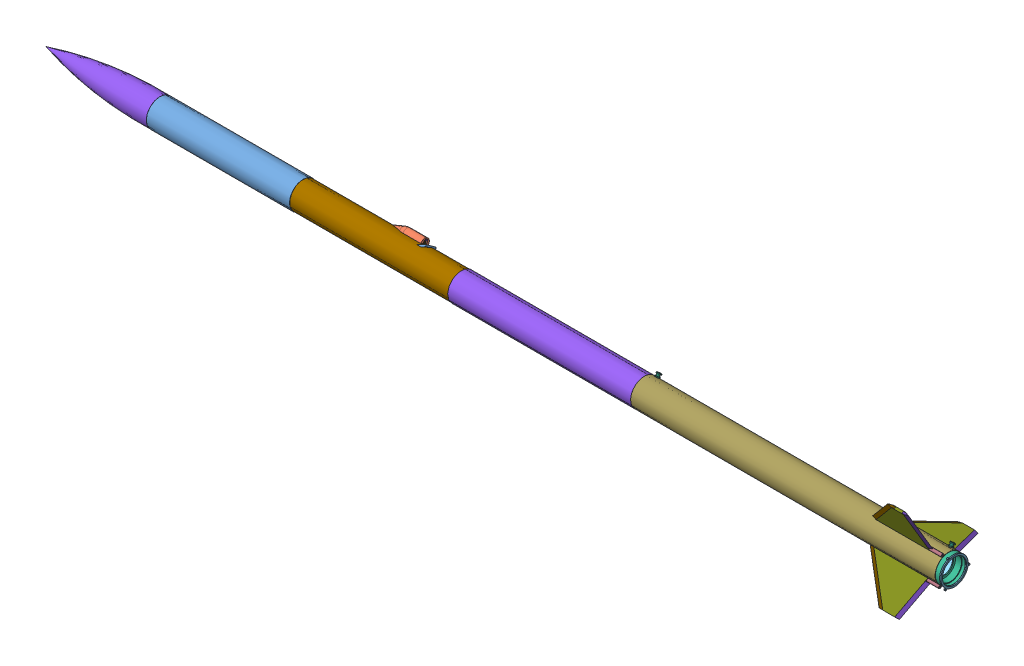
SolidWorks assembly Mudd II, configuration Default. Lengths in mm.
Overall size (1923.22 249.85 252.65).
58 component instances, 43 part files, 15 mates.
Components (placement in the parent):
- Drogue Parachute Assembly-1: Drogue Parachute Assembly [Default] at (16.0079 52.1439 -43.8729) size (341.12 76.5 76.5)
  - Drogue Tube-1: Drogue Tube [Default] at (-135.6643 44.9583 41.0442) size (303.02 58.17 58.17)
  - Drogue Coupler Tube-1: Drogue Coupler Tube [Default] at (205.4577 44.9583 41.0442) x (0 -0.693072 0.720868) z (-1 0 0) size (54.1 54.1 88.9)
  - Drogue Bulk Head (without aluminum)-1: Drogue Bulk Head (without aluminum) [Default] at (194.0277 44.9583 41.0442) x (0 0.776678 -0.629898) z (-1 0 0) size (51.82 50.33 3.81)
  - Drouge Bulk Head (with aluminum)-1: Drouge Bulk Head (with aluminum) [Default] at (194.0277 44.9583 41.0442) x (0 0.776678 -0.629898) z (-1 0 0) size (51.82 44.58 3.81)
  - Drogue Bulkhead Aluminum (with thread)-1: Drogue Bulkhead Aluminum (with thread) [Default] at (194.0277 70.4691 44.555) x (0 -0.776678 0.629898) z (1 0 0) size (35.56 15.24 4.06)
  - Drogue Bulkhead Aluminum (with tether slot)-1: Drogue Bulkhead Aluminum (with tether slot) [Default] at (202.1557 42.8505 66.9542) x (0 0.776678 -0.629898) z (-1 0 0) size (35.56 15.24 4.06)
  - Drogue Bulk Head Screw Insert-1: Drogue Bulk Head Screw Insert [Default] at (204.1877 41.1185 36.3095) x (0 1 0) z (0 0 1) size (19.05 25.4 19.05)
- Main Parachute Assembly-1: Main Parachute Assembly [Default] at (770.0138 103.0452 57.7564) x (-1 0 0) z (0 -0.800818 -0.598908) size (438.15 76.5 76.5)
  - Main Parachute Tube-1: Main Parachute Tube [Default] at (-135.6643 44.9583 41.0442) size (387.35 58.17 58.17)
  - Main Parachute Coupler Tube-1: Main Parachute Coupler Tube [Default] at (302.4857 44.9583 41.0442) x (0 -0.693072 0.720868) z (-1 0 0) size (54.1 54.1 101.6)
  - Main Parachute Bulk Head (without aluminum)-1: Main Parachute Bulk Head (without aluminum) [Default] at (291.0557 44.9583 41.0442) x (0 0.776678 -0.629898) z (-1 0 0) size (51.82 50.33 3.81)
  - Main Parachute Bulk Head (with aluminum)-1: Main Parachute Bulk Head (with aluminum) [Default] at (291.0557 44.9583 41.0442) x (0 0.776678 -0.629898) z (-1 0 0) size (51.82 44.58 3.81)
  - Main Parachute Bulkhead Aluminum (with thread)-1: Main Parachute Bulkhead Aluminum (with thread) [Default] at (291.0557 70.4691 44.555) x (0 -0.776678 0.629898) z (1 0 0) size (35.56 15.24 4.06)
  - Main Parachute Bulkhead Aluminum (with tether slot)-1: Main Parachute Bulkhead Aluminum (with tether slot) [Default] at (299.1837 42.8505 66.9542) x (0 0.776678 -0.629898) z (-1 0 0) size (35.56 15.24 4.06)
  - Main Parachute Bulk Head Screw Insert-1: Main Parachute Bulk Head Screw Insert [Default] at (301.2157 41.1185 36.3095) x (0 1 0) z (0 0 1) size (19.05 25.4 19.05)
- Booster Assembly-1: Booster Assembly [Default] at (842.1781 97.1022 -2.8288) x (0 0.913968 -0.405785) z (1 0 0) size (187.62 193.13 720.6)
  - Booster Coupler Tube-1: Booster Coupler Tube [Default] at origin size (54.1 54.1 114.3)
  - Booster Tube-1: Booster Tube [Default] at (0 0 63.5) x (0 0 1) z (-0.97847 0.20639 0) size (644.52 58.17 58.17)
  - Motor Retention Holder-1: Motor Retention Holder [Default] at (-30.9326 6.5719 682.625) x (0 0 1) z (-0.20782 -0.978167 0) size (25.4 5.77 6.35)
  - Motor Retention Holder-2: Motor Retention Holder [Default] at (21.092 23.5615 708.025) x (0 0 -1) z (0.745073 -0.666983 0) size (25.4 5.77 6.35)
  - Motor Retention Holder-3: Motor Retention Holder [Default] at (9.6678 -30.1089 708.025) x (0 0 -1) z (-0.952122 -0.305719 0) size (25.4 5.77 6.35)
  - Motor Retention Device-1: Motor Retention Device [Default] at (-5.9338 14.6913 717.55) x (-0.543056 -0.839697 0) z (0 0 1) size (61.65 59.98 2.54)
  - Rail Guide-1: Rail Guide [Default] at (33.9245 -7.1557 695.325) x (-0.161132 -0.763909 -0.624884) z (-0.128969 -0.61143 0.780718) size (9.4 7.26 9.4)
  - Fin-1: Fin [Default] at (-53.0053 -62.8554 549.8865) x (0 0 1) z (-0.744185 0.667974 0) size (114.3 76.2 5.08)
  - Fin-2: Fin [Default] at (-27.9317 77.3316 549.8865) x (0 0 1) z (0.950575 0.310496 0) size (114.3 76.2 5.08)
  - Fin-4: Fin [Default] at (80.937 -14.4762 549.8865) x (0 0 1) z (-0.20639 -0.97847 0) size (114.3 76.2 5.08)
  - Fin Insert (trailing edge)-1: Fin Insert (trailing edge) [Default] at (35.9837 -110.163 651.7234) x (-0.950575 -0.310496 0) z (-0.098188 0.300598 -0.948683) size (5.08 77.77 11.43)
  - Fin Insert (leading edge)-1: Fin Insert (leading edge) [Default] at (33.7945 -103.4608 637.2636) x (0.950575 0.310496 0) z (-0.198775 0.608543 0.768221) size (5.08 108.71 11.43)
  - Fin Insert (leading edge)-2: Fin Insert (leading edge) [Default] at (72.7024 80.9973 637.2636) x (-0.744185 0.667974 0) z (-0.427626 -0.476416 0.768221) size (5.08 108.71 11.43)
  - Fin Insert (leading edge)-3: Fin Insert (leading edge) [Default] at (-106.497 22.4635 637.2636) x (-0.20639 -0.97847 0) z (0.626401 -0.132127 0.768221) size (5.08 108.71 11.43)
  - Fin Insert (trailing edge)-2: Fin Insert (trailing edge) [Default] at (-113.3958 23.9187 651.7234) x (0.20639 0.97847 0) z (0.309419 -0.065266 -0.948683) size (5.08 77.77 11.43)
  - Fin Insert (trailing edge)-4: Fin Insert (trailing edge) [Default] at (77.4121 86.2443 651.7234) x (0.744185 -0.667974 0) z (-0.211232 -0.235332 -0.948683) size (5.08 77.77 11.43)
  - Booster Bulkhead-1: Booster Bulkhead [Default] at (0 0 7.62) x (0.186078 0.982535 0) z (0 0 1) size (51.82 51.82 3.81)
  - Booster Bulkhead Aluminum (with thread)-1: Booster Bulkhead Aluminum (with thread) [Default] at (4.1784 -18.8874 11.43) x (0.186078 0.982535 0) z (0 0 1) size (35.56 15.24 4.06)
  - Booster Bulkhead Aluminum (without thread)-1: Booster Bulkhead Aluminum (without thread) [Default] at (-10.7954 -16.0516 7.62) x (0.186078 0.982535 0) z (0 0 -1) size (35.56 15.24 4.06)
  - Booster Bulkhead Aluminum (with tether slot)-1: Booster Bulkhead Aluminum (with tether slot) [Default] at (4.1784 -18.8874 -0.508) x (0.186078 0.982535 0) z (0 0 1) size (35.56 15.24 4.06)
  - Rail Guide-2: Rail Guide [Default] at (30.0971 -6.3484 73.66) x (0.20639 0.97847 0) z (0 0 1) size (9.4 7.26 9.4)
  - Motor-1: Motor [Default] at (7.6172 -17.7558 568.7486) size (78.29 78.29 327.66)
    - Tube-1: Tube [Default] at (-7.6172 17.7558 -155.3636) size (54.1 54.1 294.64)
    - Bottom-1: Bottom [Default] at (-7.6172 17.7558 127.8464) x (-0.509484 -0.86048 0) z (0 0 1) size (57.15 57.15 20.96)
    - Top-2: Top [Default] at (-7.6172 17.7558 -142.6636) x (-0.041526 -0.999137 0) z (0 0 -1) size (54.1 54.1 36.2)
- NoseCone-1: NoseCone [Default] at (-119.6564 126.0582 -2.8288) size (297.18 58.49 58.49)
- Avionics Tube-1: Avionics Tube [Default] at (183.3656 97.1022 -2.8288) x (1 0 0) z (0 0.779036 -0.626979) size (334.96 57.15 57.15)
- AvionicsSeat-1: AvionicsSeat [Default] at (453.2842 97.1022 -2.8288) x (0 0.810541 -0.585682) z (1 0 0) size (54.23 54.18 3.81)
- MuddIIAvionicsCF-1: MuddIIAvionicsCF [Default] at (336.9706 70.1268 -24.3039) x (1 0 0) z (0 -0.585682 -0.810541) size (247.4 53.2 53.07)
  - AvionicsBed-1: AvionicsBed [Default] at (112.5036 -35.703 -35.1105) size (229.11 52.83 3.81)
  - DiscMid-1: DiscMid [Default] at (-56.6604 -9.287 -33.2055) x (0 -1 0) z (-1 0 0) size (52.76 52.69 3.81)
  - DiscForward-1: DiscForward [Default] at (-116.6044 -9.287 -33.2055) x (0 -1 0) z (-1 0 0) size (52.83 52.69 3.81)
  - DiscAft-1: DiscAft [Default] at (112.5036 -9.287 -33.2055) x (0 0.999975 0.007097) z (1 0 0) size (52.83 52.69 3.81)
  - Avionics Support 1-1: Avionics Support 1 [Default] at (-48.709 -11.192 -22.296) x (1 0 0) z (0 1 0) size (236.73 5.08 3.81)
  - Avionics Support 2-1: Avionics Support 2 [Default] at (2.2069 -7.382 -31.1739) x (1 0 0) z (0 -1 0) size (247.4 11.94 3.81)
- alternative design 3 mini cam ghetto shrouding-1: alternative design 3 mini cam ghetto shrouding [Default] at (487.2089 91.8063 -22.3354) x (1 0 0) z (0 0.585682 0.810541) size (83.75 22.14 26.02)
  - mini camera shrouding card-1: mini camera shrouding card [Default] at (-74.4625 25.279 15.7376) size (35.56 19.63 6.35)
  - mini cam-1: mini cam [Default] at (-66.747 25.71 18.9126) x (-1 0 0) z (0 0 1) size (13.56 8.59 8.59)
  - mirror piece draft 1-1: mirror piece draft 1 [Default] at (-70.5888 9.8968 33.9915) x (0 0 1) z (-0.422618 0.906308 0) size (25.4 25.4 3.2)
  - ghetto mudd II alternative design 3 shrouding-1: ghetto mudd II alternative design 3 shrouding [Default] at (-62.8608 21.4428 18.9126) size (68.45 12.66 21.88)
  - ghetto shrouding tab-1: ghetto shrouding tab [Default] at (-83.1808 21.0009 15.7376) size (19.05 7.45 6.35)
Mates (geometry in assembly coordinates):
- Concentric2: concentric anti-aligned: cylinder of Main Parachute Assembly-1/Main Parachute Tube-1; cylinder of Booster Assembly-1/Booster Coupler Tube-1
- Coincident3: coincident anti-aligned: plane of Main Parachute Assembly-1/Main Parachute Tube-1 through (905.6781 97.1022 -2.8288) normal (1 0 0); plane of Booster Assembly-1/Booster Tube-1 through (905.6781 97.1022 -2.8288) normal (-1 0 0)
- Concentric3: concentric anti-aligned: cylinder of Drogue Parachute Assembly-1/Drogue Tube-1; cylinder of NoseCone-1
- Coincident4: coincident anti-aligned: plane of Drogue Parachute Assembly-1/Drogue Tube-1 through (-119.6564 97.1022 -2.8288) normal (-1 0 0); plane of NoseCone-1 through (-119.6564 126.0582 -2.8288) normal (1 0 0)
- Concentric4: concentric anti-aligned: cylinder of Drogue Parachute Assembly-1/Drogue Coupler Tube-1; cylinder of Avionics Tube-1
- Coincident5: coincident anti-aligned: plane of Drogue Parachute Assembly-1/Drogue Tube-1 through (183.3656 97.1022 -2.8288) normal (1 0 0); plane of Avionics Tube-1 through (183.3656 97.1022 -2.8288) normal (-1 0 0)
- Concentric5: concentric aligned: cylinder of Main Parachute Assembly-1/Main Parachute Coupler Tube-1; cylinder of Avionics Tube-1
- Coincident6: coincident anti-aligned: plane of Main Parachute Assembly-1/Main Parachute Tube-1 through (518.3281 97.1022 -2.8288) normal (-1 0 0); plane of Avionics Tube-1 through (518.3281 97.1022 -2.8288) normal (1 0 0)
- Concentric6: concentric anti-aligned: cylinder of Avionics Tube-1; circle of AvionicsSeat-1 centre (457.0942 97.1022 -2.8288) axis (1 0 0)
- Coincident7: coincident anti-aligned: plane of AvionicsSeat-1 through (453.2842 97.1022 -2.8288) normal (-1 0 0); plane of MuddIIAvionicsCF-1/DiscAft-1 through (453.2842 97.1022 -2.8288) normal (1 0 0)
- Concentric7: concentric aligned: circle of AvionicsSeat-1 centre (453.2842 97.1022 -2.8288) axis (1 0 0); circle of MuddIIAvionicsCF-1/DiscAft-1 centre (453.2842 97.1022 -2.8288) axis (1 0 0)
- Parallel1: parallel aligned: line of AvionicsSeat-1; line of MuddIIAvionicsCF-1/Avionics Support 2-1
- Angle1: planar angle = 1.047198 rad aligned: plane of Booster Assembly-1/Fin-1 through (1499.4031 194.1092 37.8802) normal (0 0.409108 -0.912486); plane of MuddIIAvionicsCF-1/AvionicsBed-1 through (449.4742 76.8067 14.1867) normal (0 0.585682 0.810541)
- Concentric8: concentric anti-aligned: cylinder of Avionics Tube-1; cylinder of alternative design 3 mini cam ghetto shrouding-1/ghetto mudd II alternative design 3 shrouding-1
- Coincident10: coincident anti-aligned: plane of Avionics Tube-1 through (439.5881 115.3819 -25.6915) normal (-1 0 0); plane of alternative design 3 mini cam ghetto shrouding-1/mini camera shrouding card-1 through (439.5881 111.8968 -9.6019) normal (1 0 0)
